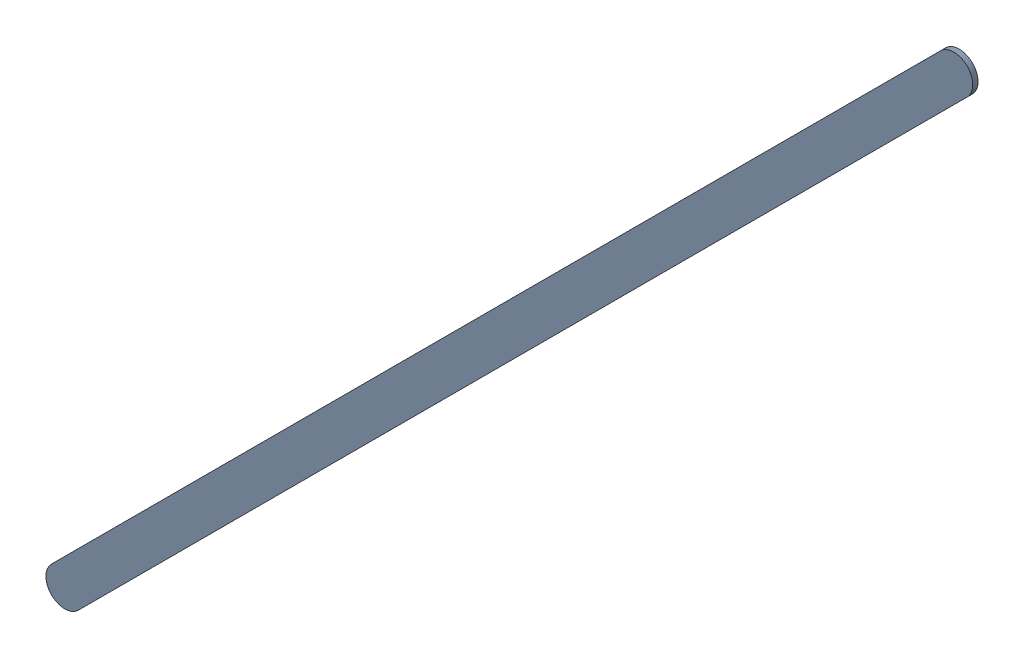
SolidWorks assembly Track (12.1mm,35.5mm)(18.08mm,41.48mm) on Bottom Layer, configuration Predeterminado. Lengths in mm.
Overall size (6.23 6.23 0.04).
2 component instances, 1 part files, 0 mates.
Components (placement in the parent):
- Track (12.1mm,35.5mm)(18.08mm,41.48mm) on Bottom Layer-1-1: Track (12.1mm,35.5mm)(18.08mm,41.48mm) on Bottom Layer-1 [Predeterminado] at (-68.317 -44.187 -0.4013) size (6.23 6.23 0.04)
  - Track (12.1mm,35.5mm)(18.08mm,41.48mm) on Bottom Layer-Part-1-1: Track (12.1mm,35.5mm)(18.08mm,41.48mm) on Bottom Layer-Part-1 [Predeterminado] at origin size (6.23 6.23 0.04)
